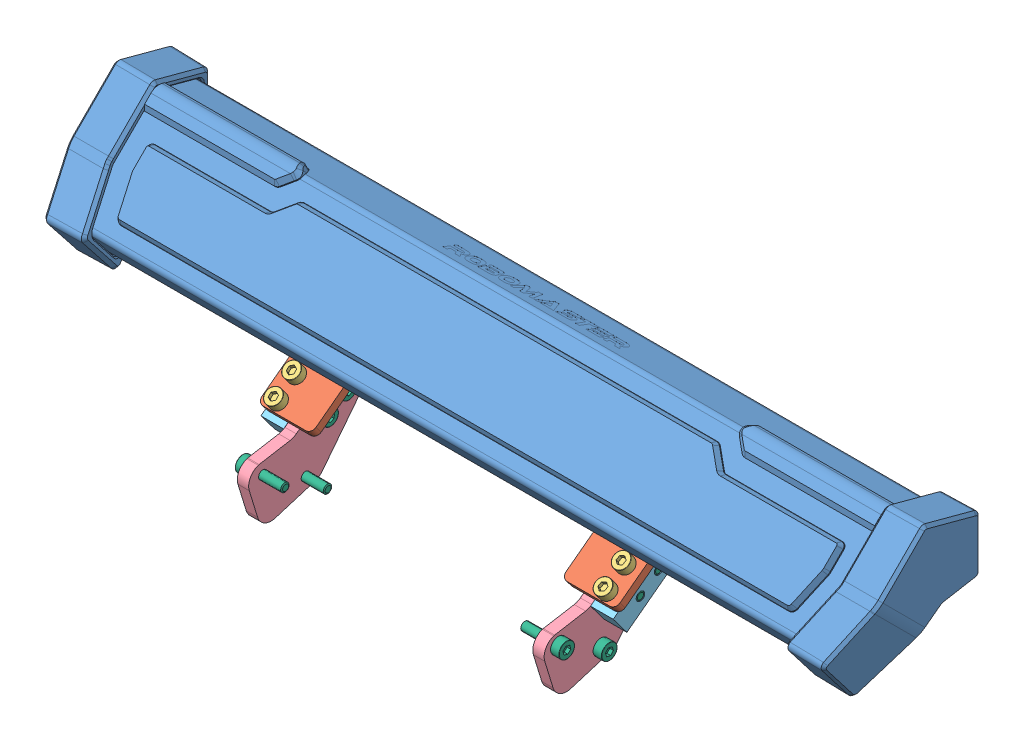
SolidWorks assembly 灯条模块, configuration 默认. Lengths in mm.
Overall size (285.02 108.97 102.24).
22 component instances, 9 part files, 43 mates.
Components (placement in the parent):
- RoboMaster 灯条模块 LI01 2020V1.3-1: RoboMaster 灯条模块 LI01 2020V1.3 [默认] at (35.5168 9.071 44.2918) size (285.02 108.97 87.07)
- 灯条支架B-1: 灯条支架B [默认] at (-39.2387 29.2005 8.4679) x (1 0 0) z (0 -0.798636 -0.601815) (suppressed, hidden)
- 灯条支架A-2: 灯条支架A [默认] at (-144.2387 29.2005 8.4679) x (1 0 0) z (0 -0.798636 -0.601815) (suppressed, hidden)
- 灯条支撑板1-1: 灯条支撑板1 [默认] at (-29.7387 13.7151 24.0328) x (1 0 0) z (0 0.798636 0.601815) size (19 42 3)
- DT-灯条支架A-1: DT-灯条支架A [默认] at (-144.2387 29.2005 8.4679) x (1 0 0) z (0 -0.798636 -0.601815) (suppressed, hidden)
- 内六角圆柱头螺钉M3×10-1: 内六角圆柱头螺钉M3×10 [Default] at (-25.2387 12.4888 35.63) x (0 -0.798636 -0.601815) z (0.399523 -0.551698 0.732128) size (13 5.5 5.5)
- 内六角圆柱头螺钉M3×10-2: 内六角圆柱头螺钉M3×10 [Default] at (-25.2387 7.6742 42.0191) x (0 -0.798636 -0.601815) z (0.399523 -0.551698 0.732128) size (13 5.5 5.5)
- 灯条支撑板2-2: 灯条支撑板2 [默认] at (-33.2387 -5.0662 37.4713) x (0 0 -1) z (1 0 0) size (39.73 33.08 4)
- 桥架接头2-M3x8-H8x22-1: 桥架接头2-M3x8-H8x22 [默认] at (-25.2387 -3.3212 39.9941) x (-1 0 0) z (0 0.601815 -0.798636) size (8 8 22)
- 灯条支撑板1-2: 灯条支撑板1 [默认] at (-136.7387 16.111 25.8382) x (-1 0 0) z (0 -0.798636 -0.601815) size (19 42 3)
- 桥架接头2-M3x8-H8x22-2: 桥架接头2-M3x8-H8x22 [默认] at (-141.2387 -3.3212 39.9941) x (-1 0 0) z (0 0.601815 -0.798636) size (8 8 22)
- 灯条支撑板2-3: 灯条支撑板2 [默认] at (-137.2387 -5.0662 37.4713) x (0 0 -1) z (1 0 0) size (39.73 33.08 4)
- 内六角圆柱头螺钉M3×10-3: 内六角圆柱头螺钉M3×10 [Default] at (-141.2387 12.4888 35.63) x (0 -0.798636 -0.601815) z (0.399523 0.551698 -0.732128) size (13 5.5 5.5)
- 内六角圆柱头螺钉M3×10-4: 内六角圆柱头螺钉M3×10 [Default] at (-141.2387 7.6742 42.0191) x (0 -0.798636 -0.601815) z (0.399523 0.551698 -0.732128) size (13 5.5 5.5)
- 内六角圆柱头M3x12-1: 内六角圆柱头M3x12 [Default] at (-130.2387 2.0951 32.8064) x (-1 0 0) z (0 -0.924225 -0.381849) size (15 5.5 5.5)
- 内六角圆柱头M3x12-2: 内六角圆柱头M3x12 [Default] at (-130.2387 6.9097 26.4173) x (-1 0 0) z (0 -0.85199 -0.523557) size (15 5.5 5.5)
- 内六角圆柱头M3x12-4: 内六角圆柱头M3x12 [Default] at (-36.2387 6.9097 26.4173) x (1 0 0) z (0 -0.282984 -0.959125) size (15 5.5 5.5)
- 内六角圆柱头M3x12-6: 内六角圆柱头M3x12 [Default] at (-36.2387 2.0951 32.8064) x (1 0 0) z (0 -0.371154 -0.928571) size (15 5.5 5.5)
- 内六角圆柱头M3x12-20: 内六角圆柱头M3x12 [Default] at (-140.2387 -6.4016 53.7096) x (1 0 0) z (0 -0.158553 -0.987351) size (15 5.5 5.5)
- 内六角圆柱头M3x12-22: 内六角圆柱头M3x12 [Default] at (-140.2387 -14.3688 38.7255) x (1 0 0) z (0 -0.282984 -0.959125) size (15 5.5 5.5)
- 内六角圆柱头M3x12-24: 内六角圆柱头M3x12 [Default] at (-26.2387 -6.4016 53.7096) x (-1 0 0) z (0 -0.716484 -0.697604) size (15 5.5 5.5)
- 内六角圆柱头M3x12-26: 内六角圆柱头M3x12 [Default] at (-26.2387 -14.3688 38.7255) x (-1 0 0) z (0 -0.677445 -0.735574) size (15 5.5 5.5)
Mates (geometry in assembly coordinates):
- 重合5: coincident anti-aligned: plane of RoboMaster 灯条模块 LI01 2020V1.3-1 through (-222.7387 14.3571 28.1657) normal (0 -0.798636 -0.601815); plane of 灯条支架B-1 through (-39.2387 29.2005 8.4679) normal (0 0.798636 0.601815)
- 重合6: coincident anti-aligned: plane of RoboMaster 灯条模块 LI01 2020V1.3-1 through (-39.2387 28.1473 9.8655) normal (1 0 0); plane of 灯条支架B-1 through (-39.2387 26.8046 6.6624) normal (-1 0 0)
- 同心1: concentric aligned: cylinder of RoboMaster 灯条模块 LI01 2020V1.3-1 through (-36.2387 24.5478 9.6573) axis (0 0.798636 0.601815) radius 1.25; cylinder of 灯条支架B-1 through (-36.2387 24.5478 9.6573) axis (0 0.798636 0.601815) radius 1.5
- 同心2: concentric aligned: cylinder of RoboMaster 灯条模块 LI01 2020V1.3-1 through (-36.2387 17.0251 19.6403) axis (0 0.798636 0.601815) radius 1.25; cylinder of 灯条支架B-1 through (-36.2387 17.0251 19.6403) axis (0 0.798636 0.601815) radius 1.5
- 重合7: coincident anti-aligned: plane of RoboMaster 灯条模块 LI01 2020V1.3-1 through (-222.7387 14.3571 28.1657) normal (0 -0.798636 -0.601815); plane of 灯条支架A-2 through (-144.2387 29.2005 8.4679) normal (0 0.798636 0.601815)
- 同心3: concentric aligned: cylinder of RoboMaster 灯条模块 LI01 2020V1.3-1 through (-130.2387 24.5478 9.6573) axis (0 0.798636 0.601815) radius 1.25; cylinder of 灯条支架A-2 through (-130.2387 24.5478 9.6573) axis (0 0.798636 0.601815) radius 1.5
- 同心4: concentric aligned: cylinder of RoboMaster 灯条模块 LI01 2020V1.3-1 through (-130.2387 17.0251 19.6403) axis (0 0.798636 0.601815) radius 1.25; cylinder of 灯条支架A-2 through (-130.2387 17.0251 19.6403) axis (0 0.798636 0.601815) radius 1.5
- 同心5: concentric anti-aligned: cylinder of RoboMaster 灯条模块 LI01 2020V1.3-1 through (-36.2387 24.5478 9.6573) axis (0 0.798636 0.601815) radius 1.25; cylinder of 灯条支撑板1-1 through (-36.2387 26.9437 11.4628) axis (0 -0.798636 -0.601815) radius 1.65
- 同心6: concentric anti-aligned: cylinder of RoboMaster 灯条模块 LI01 2020V1.3-1 through (-36.2387 17.0251 19.6403) axis (0 0.798636 0.601815) radius 1.25; cylinder of 灯条支撑板1-1 through (-36.2387 19.421 21.4457) axis (0 -0.798636 -0.601815) radius 1.65
- 重合8: coincident anti-aligned: plane of RoboMaster 灯条模块 LI01 2020V1.3-1 through (-222.7387 14.3571 28.1657) normal (0 -0.798636 -0.601815); plane of 灯条支撑板1-1 through (-29.7387 16.111 25.8382) normal (0 0.798636 0.601815)
- 同心11: concentric aligned: cylinder of 灯条支架A-2 through (-138.2387 4.2576 59.0048) axis (1 0 0) radius 1.5; cylinder of DT-灯条支架A-1 through (-138.2387 -6.4016 53.7096) axis (1 0 0) radius 1.5
- 重合11: coincident anti-aligned: plane of RoboMaster 灯条模块 LI01 2020V1.3-1 through (-222.7387 14.3571 28.1657) normal (0 -0.798636 -0.601815); plane of DT-灯条支架A-1 through (-144.2387 29.2005 8.4679) normal (0 0.798636 0.601815)
- 同心13: concentric aligned: cylinder of RoboMaster 灯条模块 LI01 2020V1.3-1 through (-130.2387 24.5478 9.6573) axis (0 0.798636 0.601815) radius 1.25; cylinder of DT-灯条支架A-1 through (-130.2387 24.5478 9.6573) axis (0 0.798636 0.601815) radius 1.5
- 同心14: concentric aligned: cylinder of RoboMaster 灯条模块 LI01 2020V1.3-1 through (-130.2387 17.0251 19.6403) axis (0 0.798636 0.601815) radius 1.25; cylinder of DT-灯条支架A-1 through (-130.2387 17.0251 19.6403) axis (0 0.798636 0.601815) radius 1.5
- 同心16: concentric aligned: cylinder of 灯条支撑板1-1 through (-25.2387 10.0929 33.8246) axis (0 -0.798636 -0.601815) radius 1.65; cylinder of 内六角圆柱头螺钉M3×10-1 through (-25.2387 12.4888 35.63) axis (0 -0.798636 -0.601815) radius 1.5
- 重合14: coincident anti-aligned: plane of 灯条支撑板1-1 through (-29.7387 16.111 25.8382) normal (0 0.798636 0.601815); plane of 内六角圆柱头螺钉M3×10-1 through (-22.7177 10.7541 32.9471) normal (0 -0.798636 -0.601815)
- 同心17: concentric aligned: cylinder of 灯条支撑板1-1 through (-25.2387 5.2783 40.2136) axis (0 -0.798636 -0.601815) radius 1.65; cylinder of 内六角圆柱头螺钉M3×10-2 through (-25.2387 7.6742 42.0191) axis (0 -0.798636 -0.601815) radius 1.5
- 重合17: coincident anti-aligned: plane of 灯条支撑板1-1 through (-29.7387 16.111 25.8382) normal (0 0.798636 0.601815); plane of 内六角圆柱头螺钉M3×10-2 through (-22.7177 5.9395 39.3362) normal (0 -0.798636 -0.601815)
- 同心18: concentric anti-aligned: cylinder of 内六角圆柱头螺钉M3×10-1 through (-25.2387 12.4888 35.63) axis (0 -0.798636 -0.601815) radius 1.5; cylinder of 桥架接头2-M3x8-H8x22-1 through (-25.2387 1.3079 27.2046) axis (0 0.798636 0.601815) radius 1.5
- 同心19: concentric anti-aligned: cylinder of 内六角圆柱头螺钉M3×10-2 through (-25.2387 7.6742 42.0191) axis (0 -0.798636 -0.601815) radius 1.5; cylinder of 桥架接头2-M3x8-H8x22-1 through (-25.2387 -3.5067 33.5937) axis (0 0.798636 0.601815) radius 1.5
- 重合19: coincident anti-aligned: plane of 灯条支撑板1-1 through (-29.7387 13.7151 24.0328) normal (0 -0.798636 -0.601815); plane of 桥架接头2-M3x8-H8x22-1 through (-21.2387 13.1133 24.8314) normal (0 0.798636 0.601815)
- 同心20: concentric aligned: cylinder of 灯条支撑板2-2 through (-29.2387 6.9097 26.4173) axis (-1 0 0) radius 1.5; cylinder of 桥架接头2-M3x8-H8x22-1 through (-21.2387 6.9097 26.4173) axis (-1 0 0) radius 1.5
- 同心21: concentric aligned: cylinder of 灯条支撑板2-2 through (-29.2387 2.0951 32.8064) axis (-1 0 0) radius 1.5; cylinder of 桥架接头2-M3x8-H8x22-1 through (-21.2387 2.0951 32.8064) axis (-1 0 0) radius 1.5
- 重合20: coincident anti-aligned: plane of 灯条支撑板2-2 through (-29.2387 -17.0087 50.7804) normal (1 0 0); plane of 桥架接头2-M3x8-H8x22-1 through (-29.2387 13.1133 24.8314) normal (-1 0 0)
- 同心22: concentric aligned: cylinder of RoboMaster 灯条模块 LI01 2020V1.3-1 through (-130.2387 24.5478 9.6573) axis (0 0.798636 0.601815) radius 1.25; cylinder of 灯条支撑板1-2 through (-130.2387 24.5478 9.6573) axis (0 0.798636 0.601815) radius 1.65
- 同心23: concentric aligned: cylinder of RoboMaster 灯条模块 LI01 2020V1.3-1 through (-130.2387 17.0251 19.6403) axis (0 0.798636 0.601815) radius 1.25; cylinder of 灯条支撑板1-2 through (-130.2387 17.0251 19.6403) axis (0 0.798636 0.601815) radius 1.65
- 重合21: coincident anti-aligned: plane of RoboMaster 灯条模块 LI01 2020V1.3-1 through (-222.7387 14.3571 28.1657) normal (0 -0.798636 -0.601815); plane of 灯条支撑板1-2 through (-136.7387 16.111 25.8382) normal (0 0.798636 0.601815)
- 同心24: concentric anti-aligned: cylinder of 灯条支撑板2-3 through (-133.2387 2.0951 32.8064) axis (-1 0 0) radius 1.5; cylinder of 内六角圆柱头M3x12-1 through (-145.2387 2.0951 32.8064) axis (1 0 0) radius 1.5
- 重合22: coincident anti-aligned: plane of 灯条支撑板2-3 through (-133.2387 -17.0087 50.7804) normal (1 0 0); plane of 内六角圆柱头M3x12-1 through (-133.2387 2.0951 32.8064) normal (-1 0 0)
- 同心25: concentric anti-aligned: cylinder of 灯条支撑板2-3 through (-133.2387 6.9097 26.4173) axis (-1 0 0) radius 1.5; cylinder of 内六角圆柱头M3x12-2 through (-145.2387 6.9097 26.4173) axis (1 0 0) radius 1.5
- 重合23: coincident anti-aligned: plane of 灯条支撑板2-3 through (-133.2387 -17.0087 50.7804) normal (1 0 0); plane of 内六角圆柱头M3x12-2 through (-133.2387 6.9097 26.4173) normal (-1 0 0)
- 同心26: concentric aligned: cylinder of 灯条支撑板2-2 through (-29.2387 6.9097 26.4173) axis (-1 0 0) radius 1.5; cylinder of 内六角圆柱头M3x12-4 through (-21.2387 6.9097 26.4173) axis (-1 0 0) radius 1.5
- 重合24: coincident aligned: circle of 灯条支撑板2-2; plane of 内六角圆柱头M3x12-4 through (-33.2387 6.9097 26.4173) normal (1 0 0)
- 同心27: concentric aligned: cylinder of 灯条支撑板2-2 through (-29.2387 2.0951 32.8064) axis (-1 0 0) radius 1.5; cylinder of 内六角圆柱头M3x12-6 through (-21.2387 2.0951 32.8064) axis (-1 0 0) radius 1.5
- 重合25: coincident anti-aligned: plane of 灯条支撑板2-2 through (-33.2387 -17.0087 50.7804) normal (-1 0 0); plane of 内六角圆柱头M3x12-6 through (-33.2387 2.0951 32.8064) normal (1 0 0)
- 同心34: concentric aligned: cylinder of 灯条支撑板2-3 through (-133.2387 -6.4016 53.7096) axis (-1 0 0) radius 1.5; cylinder of 内六角圆柱头M3x12-20 through (-125.2387 -6.4016 53.7096) axis (-1 0 0) radius 1.5
- 重合32: coincident anti-aligned: plane of 灯条支撑板2-3 through (-137.2387 -17.0087 50.7804) normal (-1 0 0); plane of 内六角圆柱头M3x12-20 through (-137.2387 -6.4016 53.7096) normal (1 0 0)
- 同心35: concentric aligned: cylinder of 灯条支撑板2-3 through (-133.2387 -14.3688 38.7255) axis (-1 0 0) radius 1.5; cylinder of 内六角圆柱头M3x12-22 through (-125.2387 -14.3688 38.7255) axis (-1 0 0) radius 1.5
- 重合33: coincident anti-aligned: plane of 灯条支撑板2-3 through (-137.2387 -17.0087 50.7804) normal (-1 0 0); plane of 内六角圆柱头M3x12-22 through (-137.2387 -14.3688 38.7255) normal (1 0 0)
- 同心36: concentric anti-aligned: cylinder of 灯条支撑板2-2 through (-29.2387 -6.4016 53.7096) axis (-1 0 0) radius 1.5; cylinder of 内六角圆柱头M3x12-24 through (-41.2387 -6.4016 53.7096) axis (1 0 0) radius 1.5
- 重合34: coincident anti-aligned: plane of 灯条支撑板2-2 through (-29.2387 -17.0087 50.7804) normal (1 0 0); plane of 内六角圆柱头M3x12-24 through (-29.2387 -6.4016 53.7096) normal (-1 0 0)
- 同心37: concentric anti-aligned: cylinder of 灯条支撑板2-2 through (-29.2387 -14.3688 38.7255) axis (-1 0 0) radius 1.5; cylinder of 内六角圆柱头M3x12-26 through (-41.2387 -14.3688 38.7255) axis (1 0 0) radius 1.5
- 重合35: coincident anti-aligned: plane of 灯条支撑板2-2 through (-29.2387 -17.0087 50.7804) normal (1 0 0); plane of 内六角圆柱头M3x12-26 through (-29.2387 -14.3688 38.7255) normal (-1 0 0)
